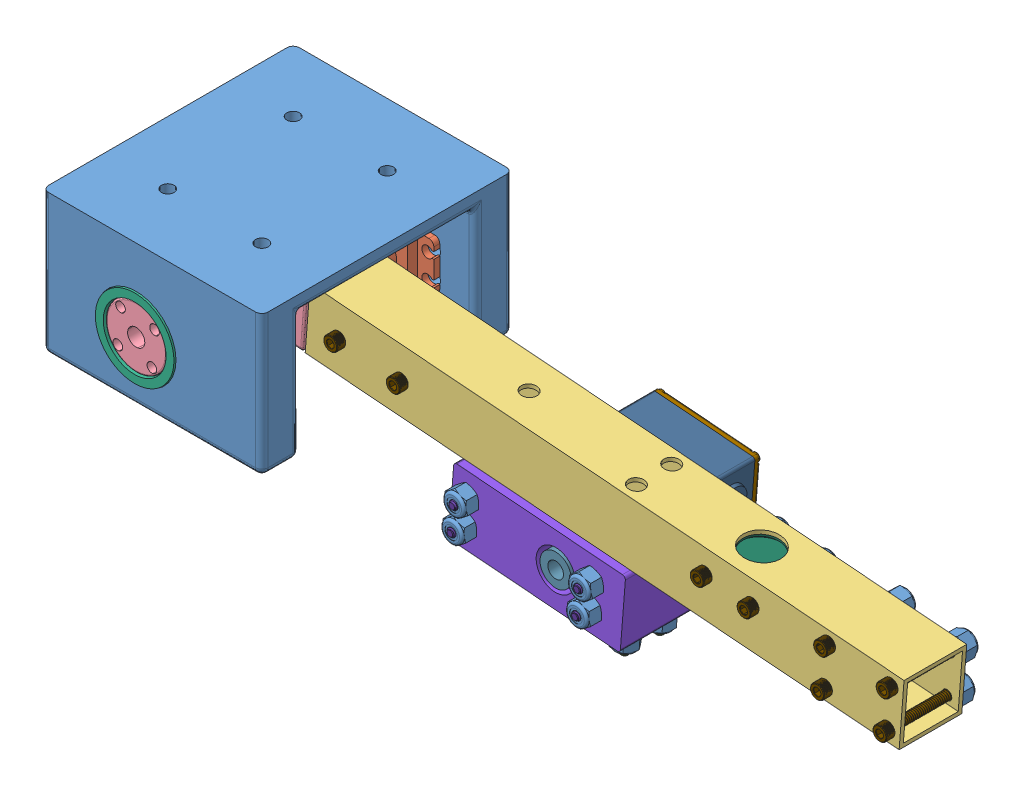
SolidWorks assembly MS-SA-0013d-03-Gripper Arm, configuration Default. Lengths in mm.
Overall size (306.45 94.86 113.6).
51 component instances, 19 part files, 106 mates.
Components (placement in the parent):
- MS-P-0057-03-Gripper Arm Mount-1: MS-P-0057-03-Gripper Arm Mount [Default] at (-52.2477 40.78 53.3156) x (0 0 1) z (0 1 0) size (101.6 88.9 57.15)
- MS-SA-0013b-03-Shoulder Servo Mount Assembly-1: MS-SA-0013b-03-Shoulder Servo Mount Assembly [Default] at (2.0387 62.0863 -50.1865) x (0 1 0) z (1 0 0) size (20 43.5 53.2)
  - MS-C-0032-Gripper Shoulder Servo-1: MS-C-0032-Gripper Shoulder Servo [Default] at (-48.0063 17.0406 -6.2663) x (0 0 -1) z (1 0 0) size (53.2 43.5 20)
- MS-P-0054-03-Box Tubing-1: MS-P-0054-03-Box Tubing [Default] at (11.7266 12.0316 -2.8819) x (0 0 -1) z (0.9969 -0.078677 0) size (25.4 25.4 241.3)
- MS-P-0058-03-Shoulder L Joint-1: MS-P-0058-03-Shoulder L Joint [Default] at (-14.2277 14.08 -2.1834) x (0 0 -1) z (0.9969 -0.078677 0) size (66.61 26.61 88.65)
- 525130.step-1: 525130.step [Default] at (-14.2277 14.08 -19.6459) x (0.078677 0.9969 0) z (0.9969 -0.078677 0) size (25.39 6.35 25.39)
- MS-C-0028-03-Servo Arm Bushing-1: MS-C-0028-03-Servo Arm Bushing [2934T25] at (-14.2277 14.08 34.9006) x (1 0 0) z (0 -1 0) size (38.1 19.05 38.1)
- 97171A170_ HEAT-SET INSERT FOR PLASTIC_V3-1: 97171A170_ HEAT-SET INSERT FOR PLASTIC_V3 [97171A170] at (19.7723 19.08 -40.131) x (-0.536856 0.843674 0) z (-0.843674 -0.536856 0) size (7.14 9.57 7.14)
- 97171A170_ HEAT-SET INSERT FOR PLASTIC_V3-2: 97171A170_ HEAT-SET INSERT FOR PLASTIC_V3 [97171A170] at (19.7723 9.08 -40.131) x (-0.383049 0.923728 0) z (-0.923728 -0.383049 0) size (7.14 9.57 7.14)
- 97171A170_ HEAT-SET INSERT FOR PLASTIC_V3-3: 97171A170_ HEAT-SET INSERT FOR PLASTIC_V3 [97171A170] at (-28.2277 19.08 -40.131) x (-0.940007 -0.341154 0) z (0.341154 -0.940007 0) size (7.14 9.57 7.14)
- 97171A170_ HEAT-SET INSERT FOR PLASTIC_V3-4: 97171A170_ HEAT-SET INSERT FOR PLASTIC_V3 [97171A170] at (-28.2277 9.08 -40.131) x (-0.231744 0.972777 0) z (-0.972777 -0.231744 0) size (7.14 9.57 7.14)
- MS-SA-0013a-03-Hand Servo Mount Assembly-1: MS-SA-0013a-03-Hand Servo Mount Assembly [Default] at (51.6986 -51.9207 16.8315) x (0 0 -1) z (0.9969 -0.078677 0) size (72.39 31.33 69.75)
  - MS-P-0055-03 Hand Servo Mount-1: MS-P-0055-03 Hand Servo Mount [Default] at (12.5808 33.9393 61.1705) size (41.76 27.94 69.75)
  - 11886-1: 11886 [Default] at (71.9223 31.717 49.4945) x (0 1 0) z (0 0 1) size (21 45.43 55.5)
    - 11886_bottom-1: 11886_bottom [Default] at (2.2223 -4.2785 0.9275) size (21 2.43 41.5)
    - 11886_middle-1: 11886_middle [Default] at (2.2223 -1.8785 0.9275) size (21 25.7 42.9)
    - 11886_upper-1: 11886_upper [Default] at (6.1473 23.8215 -5.3225) size (21 8.72 55.5)
    - 11886_top-1: 11886_top [Default] at (2.2223 32.5215 0.7275) size (20 8.6 36.5)
  - MS-C-0027-Servo Horn-1: MS-C-0027-Servo Horn [Default] at (34.0008 33.9393 61.172) x (0 0.962595 -0.270945) z (0 0.270945 0.962595) size (25.39 6.35 25.39)
  - MS-P-0060-03-Hand Servo Pulley-1: MS-P-0060-03-Hand Servo Pulley [Default] at (22.8883 33.9393 61.172) x (0 0.270945 0.962595) z (0 -0.962595 0.270945) size (25.4 23.81 25.4)
- MS-P-0047-Gripper Electromagnet Mount Inside Arm-1: MS-P-0047-Gripper Electromagnet Mount Inside Arm [Default] at (181.8873 -2.9901 -2.8819) x (0.9969 -0.078677 0) z (0 0 1) size (31.75 12.7 22.1)
- 92196A167_18-8 STAINLESS STEEL SOCKET HEAD SCREW-1: 92196A167_18-8 STAINLESS STEEL SOCKET HEAD SCREW [92196A167] at (134.4611 -47.0202 4.2619) x (0.178356 -0.014076 -0.983865) z (-0.078677 -0.9969 0) size (5.73 5.73 42.21)
- 92196A167_18-8 STAINLESS STEEL SOCKET HEAD SCREW-2: 92196A167_18-8 STAINLESS STEEL SOCKET HEAD SCREW [92196A167] at (134.4611 -47.0202 -10.0256) x (-0.009679 0.000764 -0.999953) z (-0.078677 -0.9969 0) size (5.73 5.73 42.21)
- 92196A167_18-8 STAINLESS STEEL SOCKET HEAD SCREW-3: 92196A167_18-8 STAINLESS STEEL SOCKET HEAD SCREW [92196A167] at (83.8186 -43.0235 -2.8819) x (-0.224346 0.017706 -0.974349) z (-0.078677 -0.9969 0) size (5.73 5.73 42.21)
- 92196A169_18-8 STAINLESS STEEL SOCKET HEAD SCREW-7: 92196A169_18-8 STAINLESS STEEL SOCKET HEAD SCREW [92196A169] at (79.7565 -15.0748 19.5306) x (-0.225494 0.974245 0) z (0 0 1) size (5.73 5.73 54.99)
- 92196A169_18-8 STAINLESS STEEL SOCKET HEAD SCREW-8: 92196A169_18-8 STAINLESS STEEL SOCKET HEAD SCREW [92196A169] at (78.9697 -25.0437 19.5306) x (0.191778 -0.981438 0) z (0 0 1) size (5.73 5.73 54.99)
- 92196A169_18-8 STAINLESS STEEL SOCKET HEAD SCREW-9: 92196A169_18-8 STAINLESS STEEL SOCKET HEAD SCREW [92196A169] at (130.2977 -19.0635 19.5306) x (0.056433 -0.998406 0) z (0 0 1) size (5.73 5.73 54.99)
- 92196A169_18-8 STAINLESS STEEL SOCKET HEAD SCREW-10: 92196A169_18-8 STAINLESS STEEL SOCKET HEAD SCREW [92196A169] at (129.511 -29.0325 19.5306) x (-0.049736 -0.998762 0) z (0 0 1) size (5.73 5.73 54.99)
- 92196A166_18-8 STAINLESS STEEL SOCKET HEAD SCREW-13: 92196A166_18-8 STAINLESS STEEL SOCKET HEAD SCREW [92196A166] at (172.7915 2.8236 -21.9319) x (0.59674 0.802434 0) z (0 0 -1) size (5.73 5.73 35.83)
- 92196A166_18-8 STAINLESS STEEL SOCKET HEAD SCREW-15: 92196A166_18-8 STAINLESS STEEL SOCKET HEAD SCREW [92196A166] at (191.7824 1.3248 -21.9319) x (0.615426 0.788195 0) z (0 0 -1) size (5.73 5.73 35.83)
- 90631A009_LOW-STRENGTH STEEL NYLON-INSERT LOCKNUT-1: 90631A009_LOW-STRENGTH STEEL NYLON-INSERT LOCKNUT [90631A009] at (84.493 -34.4775 -2.8819) x (-0.834574 0.065866 -0.546944) z (-0.545249 0.043032 0.837169) size (8.73 6.09 10.08)
- 90631A009_LOW-STRENGTH STEEL NYLON-INSERT LOCKNUT-2: 90631A009_LOW-STRENGTH STEEL NYLON-INSERT LOCKNUT [90631A009] at (135.1356 -38.4743 4.2619) x (-0.922375 0.072795 -0.379375) z (-0.378199 0.029848 0.925243) size (8.73 6.09 10.08)
- 90631A009_LOW-STRENGTH STEEL NYLON-INSERT LOCKNUT-3: 90631A009_LOW-STRENGTH STEEL NYLON-INSERT LOCKNUT [90631A009] at (135.1356 -38.4743 -10.0256) x (-0.982217 0.077518 -0.170998) z (-0.170468 0.013454 0.985271) size (8.73 6.09 10.08)
- 90631A009_LOW-STRENGTH STEEL NYLON-INSERT LOCKNUT-5: 90631A009_LOW-STRENGTH STEEL NYLON-INSERT LOCKNUT [90631A009] at (130.2977 -19.0635 12.9931) x (-0.987107 -0.16006 0) z (-0.16006 0.987107 0) size (8.73 6.09 10.08)
- 90631A009_LOW-STRENGTH STEEL NYLON-INSERT LOCKNUT-7: 90631A009_LOW-STRENGTH STEEL NYLON-INSERT LOCKNUT [90631A009] at (129.511 -29.0325 12.9931) x (-0.994509 -0.104651 0) z (-0.104651 0.994509 0) size (8.73 6.09 10.08)
- 90631A009_LOW-STRENGTH STEEL NYLON-INSERT LOCKNUT-9: 90631A009_LOW-STRENGTH STEEL NYLON-INSERT LOCKNUT [90631A009] at (79.7565 -15.0748 12.9931) x (-0.993677 -0.112278 0) z (-0.112278 0.993677 0) size (8.73 6.09 10.08)
- 90631A009_LOW-STRENGTH STEEL NYLON-INSERT LOCKNUT-11: 90631A009_LOW-STRENGTH STEEL NYLON-INSERT LOCKNUT [90631A009] at (78.9697 -25.0437 12.9931) x (-0.593284 0.804993 0) z (0.804993 0.593284 0) size (8.73 6.09 10.08)
- 90631A009_LOW-STRENGTH STEEL NYLON-INSERT LOCKNUT-13: 90631A009_LOW-STRENGTH STEEL NYLON-INSERT LOCKNUT [90631A009] at (191.7824 1.3248 -15.5819) x (0.013782 -0.999905 0) z (0.999905 0.013782 0) size (8.73 6.09 10.08)
- 90631A009_LOW-STRENGTH STEEL NYLON-INSERT LOCKNUT-15: 90631A009_LOW-STRENGTH STEEL NYLON-INSERT LOCKNUT [90631A009] at (172.7915 2.8236 -15.5819) x (0.187204 -0.982321 0) z (0.982321 0.187204 0) size (8.73 6.09 10.08)
- 92196A166_18-8 STAINLESS STEEL SOCKET HEAD SCREW-17: 92196A166_18-8 STAINLESS STEEL SOCKET HEAD SCREW [92196A166] at (222.7709 3.338 -21.9319) x (-0.902884 0.429884 0) z (0 0 -1) size (5.73 5.73 35.83)
- 92196A166_18-8 STAINLESS STEEL SOCKET HEAD SCREW-18: 92196A166_18-8 STAINLESS STEEL SOCKET HEAD SCREW [92196A166] at (248.0921 1.3396 -21.9319) x (0.224376 0.974503 0) z (0 0 -1) size (5.73 5.73 35.83)
- 92196A166_18-8 STAINLESS STEEL SOCKET HEAD SCREW-19: 92196A166_18-8 STAINLESS STEEL SOCKET HEAD SCREW [92196A166] at (221.5219 -12.4878 -21.9319) x (0.278925 0.960313 0) z (0 0 -1) size (5.73 5.73 35.83)
- 92196A166_18-8 STAINLESS STEEL SOCKET HEAD SCREW-20: 92196A166_18-8 STAINLESS STEEL SOCKET HEAD SCREW [92196A166] at (246.8431 -14.4862 -21.9319) x (0.226233 0.974073 0) z (0 0 -1) size (5.73 5.73 35.83)
- 92196A166_18-8 STAINLESS STEEL SOCKET HEAD SCREW-21: 92196A166_18-8 STAINLESS STEEL SOCKET HEAD SCREW [92196A166] at (24.3873 11.0324 -21.9319) x (0.216747 0.976228 0) z (0 0 -1) size (5.73 5.73 35.83)
- 92196A166_18-8 STAINLESS STEEL SOCKET HEAD SCREW-22: 92196A166_18-8 STAINLESS STEEL SOCKET HEAD SCREW [92196A166] at (49.7085 9.0341 -21.9319) x (0.256336 0.966588 0) z (0 0 -1) size (5.73 5.73 35.83)
- 90631A009_LOW-STRENGTH STEEL NYLON-INSERT LOCKNUT-16: 90631A009_LOW-STRENGTH STEEL NYLON-INSERT LOCKNUT [90631A009] at (222.7709 3.338 -15.5819) x (-0.973129 -0.230259 0) z (0.230259 -0.973129 0) size (8.73 6.09 10.08)
- 90631A009_LOW-STRENGTH STEEL NYLON-INSERT LOCKNUT-17: 90631A009_LOW-STRENGTH STEEL NYLON-INSERT LOCKNUT [90631A009] at (248.0921 1.3396 -15.5819) x (0.296175 -0.955134 0) z (0.955134 0.296175 0) size (8.73 6.09 10.08)
- 90631A009_LOW-STRENGTH STEEL NYLON-INSERT LOCKNUT-18: 90631A009_LOW-STRENGTH STEEL NYLON-INSERT LOCKNUT [90631A009] at (221.5219 -12.4878 -15.5819) x (0.383916 -0.923368 0) z (0.923368 0.383916 0) size (8.73 6.09 10.08)
- 90631A009_LOW-STRENGTH STEEL NYLON-INSERT LOCKNUT-19: 90631A009_LOW-STRENGTH STEEL NYLON-INSERT LOCKNUT [90631A009] at (246.8431 -14.4862 -15.5819) x (0.433613 -0.901099 0) z (0.901099 0.433613 0) size (8.73 6.09 10.08)
- 90631A009_LOW-STRENGTH STEEL NYLON-INSERT LOCKNUT-20: 90631A009_LOW-STRENGTH STEEL NYLON-INSERT LOCKNUT [90631A009] at (49.7085 9.0341 -15.5819) x (0.442359 -0.896838 0) z (0.896838 0.442359 0) size (8.73 6.09 10.08)
- 90631A009_LOW-STRENGTH STEEL NYLON-INSERT LOCKNUT-21: 90631A009_LOW-STRENGTH STEEL NYLON-INSERT LOCKNUT [90631A009] at (24.3873 11.0324 -15.5819) x (-0.623475 -0.781844 0) z (0.781844 -0.623475 0) size (8.73 6.09 10.08)
Mates (geometry in assembly coordinates):
- Distance1: distance = 6.35 mm anti-aligned: plane of MS-P-0047 - Gripper Arm Mount-1 through (95.6161 2.1794 54.1355) normal (0 0 -1); plane of GripperArm-1 through (52.9892 28.9852 43.023) normal (0 0 1)
- Concentric2: concentric aligned: cylinder of GripperArm-1 through (57.5161 21.2294 36.673) axis (0 0 1) radius 3.9688; cylinder of 6389K231_LIGHT DUTY DRY-RUNNING SLEEVE BEARING-1 through (19.4161 14.8794 63.9267) axis (0 0 1) radius 4.7625
- Coincident3: coincident anti-aligned: plane of MS-P-0057-03-Gripper Arm Mount-1 through (36.6523 47.13 53.3156) normal (0 0 1); plane of 6389K231_LIGHT DUTY DRY-RUNNING SLEEVE BEARING-2 through (19.4161 14.8794 69.3755) normal (0 0 -1)
- Concentric4: concentric anti-aligned: cylinder of 6389K231_LIGHT DUTY DRY-RUNNING SLEEVE BEARING-2 through (19.4161 14.8794 63.0255) axis (0 0 1) radius 3.175; cylinder of 90325A181_18-8 STAINLESS STEEL PRECISION SHOULDER SCREW-1 through (14.5574 87.2469 34.4811) axis (0 0 -1) radius 3.175
- Coincident4: coincident anti-aligned: plane of 6389K231_LIGHT DUTY DRY-RUNNING SLEEVE BEARING-2 through (19.4161 14.8794 70.963) normal (0 0 1); plane of 90325A181_18-8 STAINLESS STEEL PRECISION SHOULDER SCREW-1 through (14.5574 82.4844 59.8811) normal (0 0 -1)
- Concentric5: concentric anti-aligned: cylinder of 90325A181_18-8 STAINLESS STEEL PRECISION SHOULDER SCREW-1 through (14.5574 87.2469 34.4811) axis (0 0 -1) radius 1.6764; circle of 90631A011_LOW-STRENGTH STEEL NYLON-INSERT LOCKNUT-1
- Coincident5: coincident anti-aligned: plane of MS-P-0057-03-Gripper Arm Mount-1 through (36.6523 -10.02 38.0756) normal (0 0 -1); plane of 90631A011_LOW-STRENGTH STEEL NYLON-INSERT LOCKNUT-1 through (19.9239 88.4479 56.6755) normal (0 0 1)
- Concentric6: concentric aligned: cylinder of GripperArm-1 through (57.5161 21.2294 36.673) axis (0 0 1) radius 3.9688; cylinder of 98002A930_STEEL BINDING BARRELS AND SCREWS-1 through (19.4161 14.8794 61.9826) axis (0 0 1) radius 3.175
- Coincident6: coincident anti-aligned: plane of GripperArm-1 through (52.9892 28.9852 36.673) normal (0 0 -1); plane of 98002A930_STEEL BINDING BARRELS AND SCREWS-1 through (19.4161 14.8794 70.9629) normal (0 0 1)
- Coincident13: coincident anti-aligned: plane of MS-P-0057-03-Gripper Arm Mount-1 through (36.6523 -10.02 -33.0444) normal (0 0 1); plane of MS-A-0013 - Gripper Arm-1/MS-P-0048 - Servo Mount Piece-3 through (57.5161 40.2794 -42.3845) normal (0 0 -1)
- Concentric12: concentric anti-aligned: cylinder of MS-P-0057-03-Gripper Arm Mount-1 through (3.6323 28.08 53.3166) axis (0 0 -1) radius 2.54; cylinder of MS-A-0013 - Gripper Arm-1/MS-P-0048 - Servo Mount Piece-3 through (76.5661 40.2794 -42.3845) axis (0 0 1) radius 2.54
- Parallel1: parallel anti-aligned: cylinder of MS-P-0057-03-Gripper Arm Mount-1 through (-31.9277 -19.92 53.3166) axis (0 0 -1) radius 2.54; cylinder of MS-A-0013 - Gripper Arm-1/MS-P-0048 - Servo Mount Piece-4 through (38.6261 -10.4206 -42.3845) axis (0 0 1) radius 2.54
- Concentric15: concentric anti-aligned: cylinder of MS-P-0057-03-Gripper Arm Mount-1 through (-31.9277 28.08 53.3166) axis (0 0 -1) radius 2.54; cylinder of MS-A-0013 - Gripper Arm-1/MS-P-0048 - Servo Mount Piece-3 through (38.4661 40.2794 -42.3845) axis (0 0 1) radius 2.54
- Concentric16: concentric anti-aligned: circle of MS-P-0049- Gripper Arm Servo Horn Mount-1; circle of 525130.step-1
- Coincident15: coincident anti-aligned: plane of MS-P-0058-03-Shoulder L Joint-1 through (-14.2277 14.08 -13.2959) normal (0 0 -1); plane of 525130.step-1 through (-14.2277 14.08 -13.2959) normal (0 0 1)
- Concentric18: concentric anti-aligned: circle of MS-A-0013 - Gripper Arm-1/11886-2/11886_top-1; circle of 525130.step-1
- Coincident16: coincident anti-aligned: plane of MS-A-0013 - Gripper Arm-1/11886-2/11886_top-1 through (63.8475 25.5794 10.7295) normal (0 0 1); plane of 525130.step-1 through (-14.2277 14.08 -16.3439) normal (0 0 -1)
- Concentric20: concentric anti-aligned: circle of MS-A-0013 - Gripper Arm-1/MS-P-0048 - Servo Mount Piece-6; circle of MS-P-0047 - Gripper Arm Mount-1
- Coincident17: coincident anti-aligned: plane of MS-P-0057-03-Gripper Arm Mount-1 through (36.6523 -10.02 -33.0444) normal (0 0 1); plane of MS-A-0013 - Gripper Arm-1/MS-P-0048 - Servo Mount Piece-6 through (-14.1477 -19.92 -58.4444) normal (0 0 -1)
- Distance2: distance = 0.635 mm anti-aligned: plane of MS-P-0054-03-Box Tubing-1 through (11.7266 12.0316 -2.8819) normal (-0.9969 0.078677 0); plane of MS-P-0058-03-Shoulder L Joint-1 through (11.0936 12.0816 10.5166) normal (0.9969 -0.078677 0)
- Coincident20: coincident anti-aligned: plane of MS-P-0057-03-Gripper Arm Mount-1 through (36.6523 -10.02 38.0756) normal (0 0 -1); plane of MS-C-0028-03-Servo Arm Bushing-1 through (-14.2277 14.08 38.0756) normal (0 0 1)
- Concentric23: concentric aligned: cylinder of MS-P-0058-03-Shoulder L Joint-1 through (-14.2277 14.08 10.5166) axis (0 0 -1) radius 12.446; cylinder of MS-C-0028-03-Servo Arm Bushing-1 through (-14.2277 14.08 53.9506) axis (0 0 -1) radius 15.9004
- Concentric24: concentric aligned: circle of MS-A-0013 - Gripper Arm-1/MS-C-0029 - D956-WP Servo-1; circle of 525130.step-1
- Coincident21: coincident anti-aligned: plane of MS-A-0013b-03-Shoulder Servo Mount Assembly-1/MS-C-0032-Gripper Shoulder Servo-1 through (-14.2277 14.08 -19.6459) normal (0 0 1); plane of 525130.step-1 through (-14.2277 14.08 -19.6459) normal (0 0 -1)
- Width1: width anti-aligned: plane of MS-P-0058-03-Shoulder L Joint-1 through (60.9168 -2.2969 7.5321) normal (0 0 1); plane of MS-P-0058-03-Shoulder L Joint-1 through (-14.2277 14.08 -13.2959) normal (0 0 -1); plane of MS-P-0054-03-Box Tubing-1 through (253.2779 5.7076 -15.5819) normal (0 0 -1); plane of MS-P-0054-03-Box Tubing-1 through (253.2779 5.7076 9.8181) normal (0 0 1)
- Width2: width aligned: plane of MS-P-0058-03-Shoulder L Joint-1 through (60.9168 -2.2969 -13.2959) normal (-0.078677 -0.9969 0); plane of MS-P-0058-03-Shoulder L Joint-1 through (62.5555 18.4665 -13.2959) normal (0.078677 0.9969 0); plane of MS-P-0054-03-Box Tubing-1 through (251.2795 -19.6136 9.8181) normal (-0.078677 -0.9969 0); plane of MS-P-0054-03-Box Tubing-1 through (253.2779 5.7076 9.8181) normal (0.078677 0.9969 0)
- Concentric25: concentric aligned: circle of MS-P-0057-03-Gripper Arm Mount-1; circle of MS-C-0028-03-Servo Arm Bushing-1
- Coincident23: coincident aligned: plane of MS-P-0057-03-Gripper Arm Mount-1 through (36.6523 47.13 53.3156) normal (0 0 1); plane of MS-P-0058-03-Shoulder L Joint-1 through (-14.2277 14.08 53.3156) normal (0 0 1)
- Parallel2: parallel aligned: plane of MS-P-0057-03-Gripper Arm Mount-1 through (-52.2477 47.13 53.3156) normal (0 1 0); plane of MS-A-0013b-03-Shoulder Servo Mount Assembly-1/MS-C-0032-Gripper Shoulder Servo-1 through (-4.2277 24.08 -30.6459) normal (0 1 0)
- Concentric26: concentric aligned: circle of MS-P-0057-03-Gripper Arm Mount-1; circle of 97171A170_ HEAT-SET INSERT FOR PLASTIC_V3-1
- Coincident24: coincident anti-aligned: plane of MS-P-0057-03-Gripper Arm Mount-1 through (36.6523 47.13 -48.2844) normal (0 0 -1); plane of 97171A170_ HEAT-SET INSERT FOR PLASTIC_V3-1 through (18.4701 21.1265 -48.2844) normal (0 0 1)
- Concentric27: concentric aligned: circle of MS-P-0057-03-Gripper Arm Mount-1; circle of 97171A170_ HEAT-SET INSERT FOR PLASTIC_V3-2
- Coincident25: coincident anti-aligned: plane of MS-P-0057-03-Gripper Arm Mount-1 through (36.6523 47.13 -48.2844) normal (0 0 -1); plane of 97171A170_ HEAT-SET INSERT FOR PLASTIC_V3-2 through (18.8432 11.3207 -48.2844) normal (0 0 1)
- Concentric28: concentric anti-aligned: circle of MS-A-0013b-03-Shoulder Servo Mount Assembly-1/MS-C-0032-Gripper Shoulder Servo-1; circle of 97171A170_ HEAT-SET INSERT FOR PLASTIC_V3-3
- Coincident27: coincident anti-aligned: plane of MS-P-0057-03-Gripper Arm Mount-1 through (36.6523 47.13 -48.2844) normal (0 0 -1); plane of 97171A170_ HEAT-SET INSERT FOR PLASTIC_V3-3 through (-30.5078 18.2524 -48.2844) normal (0 0 1)
- Concentric29: concentric aligned: circle of MS-A-0013b-03-Shoulder Servo Mount Assembly-1/MS-C-0032-Gripper Shoulder Servo-1; circle of 97171A170_ HEAT-SET INSERT FOR PLASTIC_V3-4
- Coincident28: coincident anti-aligned: plane of MS-P-0057-03-Gripper Arm Mount-1 through (36.6523 47.13 -48.2844) normal (0 0 -1); plane of 97171A170_ HEAT-SET INSERT FOR PLASTIC_V3-4 through (-28.7898 11.4396 -48.2844) normal (0 0 1)
- Coincident29: coincident anti-aligned: plane of MS-P-0057-03-Gripper Arm Mount-1 through (36.6523 -10.02 -33.0444) normal (0 0 1); plane of 97171A170_ HEAT-SET INSERT FOR PLASTIC_V3-5 through (25.2931 19.7789 -33.0444) normal (0 0 -1)
- Coincident30: coincident anti-aligned: plane of MS-P-0057-03-Gripper Arm Mount-1 through (36.6523 -10.02 -33.0444) normal (0 0 1); plane of 97171A170_ HEAT-SET INSERT FOR PLASTIC_V3-6 through (25.6708 9.88 -33.0444) normal (0 0 -1)
- Concentric30: concentric aligned: circle of MS-P-0054-03-Box Tubing-1; circle of MS-SA-0013a-03-Hand Servo Mount Assembly-1/MS-P-0055-03 Hand Servo Mount-1
- Concentric31: concentric aligned: circle of MS-P-0054-03-Box Tubing-1; circle of MS-SA-0013a-03-Hand Servo Mount Assembly-1/MS-P-0055-03 Hand Servo Mount-1
- Coincident31: coincident anti-aligned: plane of MS-P-0054-03-Box Tubing-1 through (251.2795 -19.6136 9.8181) normal (-0.078677 -0.9969 0); plane of MS-SA-0013a-03-Hand Servo Mount Assembly-1/MS-P-0055-03 Hand Servo Mount-1 through (116.4488 -8.9727 88.1295) normal (0.078677 0.9969 0)
- Width3: width anti-aligned: plane of MS-P-0054-03-Box Tubing-1 through (253.153 4.125 8.2306) normal (0 0 -1); plane of MS-P-0054-03-Box Tubing-1 through (253.153 4.125 -13.9944) normal (0 0 1); plane of MS-P-0047-Gripper Electromagnet Mount Inside Arm-1 through (167.0607 10.9195 8.1671) normal (0 0 1); plane of MS-P-0047-Gripper Electromagnet Mount Inside Arm-1 through (167.0607 10.9195 -13.9309) normal (0 0 -1)
- Coincident32: coincident anti-aligned: plane of MS-P-0054-03-Box Tubing-1 through (253.153 4.125 8.2306) normal (-0.078677 -0.9969 0); plane of MS-P-0047-Gripper Electromagnet Mount Inside Arm-1 through (182.8864 9.6706 -2.8819) normal (0.078677 0.9969 0)
- Concentric32: concentric aligned: circle of MS-P-0054-03-Box Tubing-1; circle of MS-P-0047-Gripper Electromagnet Mount Inside Arm-1
- LimitAngle1: limit planar angle = 0.078758 rad aligned: plane of MS-P-0054-03-Box Tubing-1 through (253.2779 5.7076 9.8181) normal (0.078677 0.9969 0); plane of MS-P-0057-03-Gripper Arm Mount-1 through (-52.2477 47.13 53.3156) normal (0 1 0)
- Concentric33: concentric aligned: circle of MS-SA-0013a-03-Hand Servo Mount Assembly-1/MS-P-0055-03 Hand Servo Mount-1; circle of 92196A169_18-8 STAINLESS STEEL SOCKET HEAD SCREW-1
- Coincident36: coincident anti-aligned: plane of MS-P-0054-03-Box Tubing-1 through (251.4044 -18.0311 8.2306) normal (0.078677 0.9969 0); plane of 92196A167_18-8 STAINLESS STEEL SOCKET HEAD SCREW-1 through (137.4587 -9.0383 4.2619) normal (-0.078677 -0.9969 0)
- Concentric34: concentric aligned: circle of MS-SA-0013a-03-Hand Servo Mount Assembly-1/MS-P-0055-03 Hand Servo Mount-1; circle of 92196A169_18-8 STAINLESS STEEL SOCKET HEAD SCREW-2
- Coincident37: coincident anti-aligned: plane of MS-P-0054-03-Box Tubing-1 through (251.4044 -18.0311 8.2306) normal (0.078677 0.9969 0); plane of 92196A167_18-8 STAINLESS STEEL SOCKET HEAD SCREW-2 through (137.4587 -9.0383 -10.0256) normal (-0.078677 -0.9969 0)
- Coincident38: coincident anti-aligned: plane of MS-P-0054-03-Box Tubing-1 through (251.4044 -18.0311 8.2306) normal (0.078677 0.9969 0); plane of 92196A167_18-8 STAINLESS STEEL SOCKET HEAD SCREW-3 through (86.8161 -5.0416 -2.8819) normal (-0.078677 -0.9969 0)
- Concentric35: concentric aligned: circle of MS-SA-0013a-03-Hand Servo Mount Assembly-1/MS-P-0055-03 Hand Servo Mount-1; circle of 92196A169_18-8 STAINLESS STEEL SOCKET HEAD SCREW-3
- Concentric37: concentric aligned: circle of MS-SA-0013a-03-Hand Servo Mount Assembly-1/MS-P-0055-03 Hand Servo Mount-1; circle of 92196A169_18-8 STAINLESS STEEL SOCKET HEAD SCREW-7
- Concentric38: concentric aligned: circle of MS-SA-0013a-03-Hand Servo Mount Assembly-1/MS-P-0055-03 Hand Servo Mount-1; circle of 92196A169_18-8 STAINLESS STEEL SOCKET HEAD SCREW-8
- Concentric39: concentric aligned: circle of MS-SA-0013a-03-Hand Servo Mount Assembly-1/MS-P-0055-03 Hand Servo Mount-1; circle of 92196A169_18-8 STAINLESS STEEL SOCKET HEAD SCREW-9
- Concentric40: concentric aligned: circle of MS-SA-0013a-03-Hand Servo Mount Assembly-1/MS-P-0055-03 Hand Servo Mount-1; circle of 92196A169_18-8 STAINLESS STEEL SOCKET HEAD SCREW-10
- Concentric41: concentric aligned: circle of MS-P-0047-Gripper Electromagnet Mount Inside Arm-1; circle of 92196A169_18-8 STAINLESS STEEL SOCKET HEAD SCREW-13
- Concentric42: concentric aligned: circle of MS-P-0047-Gripper Electromagnet Mount Inside Arm-1; circle of 92196A169_18-8 STAINLESS STEEL SOCKET HEAD SCREW-15
- Concentric43: concentric anti-aligned: circle of 90631A009_LOW-STRENGTH STEEL NYLON-INSERT LOCKNUT-1; circle of MS-SA-0013a-03-Hand Servo Mount Assembly-1/MS-P-0055-03 Hand Servo Mount-1
- Coincident52: coincident anti-aligned: plane of MS-SA-0013a-03-Hand Servo Mount Assembly-1/MS-P-0055-03 Hand Servo Mount-1 through (114.2506 -36.826 88.1295) normal (-0.078677 -0.9969 0); plane of 90631A009_LOW-STRENGTH STEEL NYLON-INSERT LOCKNUT-1 through (92.2594 -35.0905 -6.8244) normal (0.078677 0.9969 0)
- Concentric44: concentric anti-aligned: circle of MS-SA-0013a-03-Hand Servo Mount Assembly-1/MS-P-0055-03 Hand Servo Mount-1; circle of 90631A009_LOW-STRENGTH STEEL NYLON-INSERT LOCKNUT-2
- Coincident53: coincident anti-aligned: plane of MS-SA-0013a-03-Hand Servo Mount Assembly-1/MS-P-0055-03 Hand Servo Mount-1 through (114.2506 -36.826 88.1295) normal (-0.078677 -0.9969 0); plane of 90631A009_LOW-STRENGTH STEEL NYLON-INSERT LOCKNUT-2 through (142.022 -39.0178 -1.0781) normal (0.078677 0.9969 0)
- Coincident54: coincident anti-aligned: plane of MS-SA-0013a-03-Hand Servo Mount Assembly-1/MS-P-0055-03 Hand Servo Mount-1 through (114.2506 -36.826 88.1295) normal (-0.078677 -0.9969 0); plane of 90631A009_LOW-STRENGTH STEEL NYLON-INSERT LOCKNUT-3 through (140.7125 -38.9145 -16.7292) normal (0.078677 0.9969 0)
- Concentric45: concentric anti-aligned: circle of MS-SA-0013a-03-Hand Servo Mount Assembly-1/MS-P-0055-03 Hand Servo Mount-1; circle of 90631A009_LOW-STRENGTH STEEL NYLON-INSERT LOCKNUT-3
- Coincident57: coincident anti-aligned: plane of MS-SA-0013a-03-Hand Servo Mount Assembly-1/11886-1/11886_upper-1 through (83.1227 -30.8886 -31.2694) normal (0 0 -1); plane of 92196A169_18-8 STAINLESS STEEL SOCKET HEAD SCREW-7 through (79.7565 -15.0748 -31.2694) normal (0 0 1)
- Coincident58: coincident anti-aligned: plane of MS-SA-0013a-03-Hand Servo Mount Assembly-1/11886-1/11886_upper-1 through (83.1227 -30.8886 -31.2694) normal (0 0 -1); plane of 92196A169_18-8 STAINLESS STEEL SOCKET HEAD SCREW-8 through (78.9697 -25.0437 -31.2694) normal (0 0 1)
- Coincident59: coincident anti-aligned: plane of MS-SA-0013a-03-Hand Servo Mount Assembly-1/11886-1/11886_upper-1 through (83.1227 -30.8886 -31.2694) normal (0 0 -1); plane of 92196A169_18-8 STAINLESS STEEL SOCKET HEAD SCREW-9 through (130.2977 -19.0635 -31.2694) normal (0 0 1)
- Coincident60: coincident anti-aligned: plane of MS-SA-0013a-03-Hand Servo Mount Assembly-1/11886-1/11886_upper-1 through (83.1227 -30.8886 -31.2694) normal (0 0 -1); plane of 92196A169_18-8 STAINLESS STEEL SOCKET HEAD SCREW-10 through (129.511 -29.0325 -31.2694) normal (0 0 1)
- Concentric47: concentric anti-aligned: circle of MS-SA-0013a-03-Hand Servo Mount Assembly-1/MS-P-0055-03 Hand Servo Mount-1; circle of 90631A009_LOW-STRENGTH STEEL NYLON-INSERT LOCKNUT-5
- Coincident61: coincident anti-aligned: plane of MS-SA-0013a-03-Hand Servo Mount Assembly-1/MS-P-0055-03 Hand Servo Mount-1 through (115.3512 -22.8995 12.9931) normal (0 0 1); plane of 90631A009_LOW-STRENGTH STEEL NYLON-INSERT LOCKNUT-5 through (135.8174 -25.8288 12.9931) normal (0 0 -1)
- Concentric50: concentric anti-aligned: circle of MS-SA-0013a-03-Hand Servo Mount Assembly-1/MS-P-0055-03 Hand Servo Mount-1; circle of 90631A009_LOW-STRENGTH STEEL NYLON-INSERT LOCKNUT-7
- Coincident63: coincident anti-aligned: plane of MS-SA-0013a-03-Hand Servo Mount Assembly-1/MS-P-0055-03 Hand Servo Mount-1 through (115.3512 -22.8995 12.9931) normal (0 0 1); plane of 90631A009_LOW-STRENGTH STEEL NYLON-INSERT LOCKNUT-7 through (134.6439 -36.0956 12.9931) normal (0 0 -1)
- Concentric51: concentric anti-aligned: circle of MS-SA-0013a-03-Hand Servo Mount Assembly-1/MS-P-0055-03 Hand Servo Mount-1; circle of 90631A009_LOW-STRENGTH STEEL NYLON-INSERT LOCKNUT-9
- Coincident64: coincident anti-aligned: plane of MS-SA-0013a-03-Hand Servo Mount Assembly-1/MS-P-0055-03 Hand Servo Mount-1 through (115.3512 -22.8995 12.9931) normal (0 0 1); plane of 90631A009_LOW-STRENGTH STEEL NYLON-INSERT LOCKNUT-9 through (84.9435 -22.0983 12.9931) normal (0 0 -1)
- Concentric52: concentric anti-aligned: circle of MS-SA-0013a-03-Hand Servo Mount Assembly-1/MS-P-0055-03 Hand Servo Mount-1; circle of 90631A009_LOW-STRENGTH STEEL NYLON-INSERT LOCKNUT-11
- Coincident65: coincident anti-aligned: plane of MS-SA-0013a-03-Hand Servo Mount Assembly-1/MS-P-0055-03 Hand Servo Mount-1 through (115.3512 -22.8995 12.9931) normal (0 0 1); plane of 90631A009_LOW-STRENGTH STEEL NYLON-INSERT LOCKNUT-11 through (75.4728 -33.0441 12.9931) normal (0 0 -1)
- Concentric53: concentric anti-aligned: circle of MS-P-0054-03-Box Tubing-1; circle of 90631A009_LOW-STRENGTH STEEL NYLON-INSERT LOCKNUT-13
- Coincident66: coincident anti-aligned: plane of MS-P-0054-03-Box Tubing-1 through (253.2779 5.7076 -15.5819) normal (0 0 -1); plane of 90631A009_LOW-STRENGTH STEEL NYLON-INSERT LOCKNUT-13 through (184.1615 5.5858 -15.5819) normal (0 0 1)
- Concentric54: concentric anti-aligned: circle of MS-P-0054-03-Box Tubing-1; circle of 90631A009_LOW-STRENGTH STEEL NYLON-INSERT LOCKNUT-15
- Coincident67: coincident anti-aligned: plane of MS-P-0054-03-Box Tubing-1 through (253.2779 5.7076 -15.5819) normal (0 0 -1); plane of 90631A009_LOW-STRENGTH STEEL NYLON-INSERT LOCKNUT-15 through (164.5464 5.6965 -15.5819) normal (0 0 1)
- Coincident68: coincident anti-aligned: plane of MS-P-0054-03-Box Tubing-1 through (253.2779 5.7076 9.8181) normal (0 0 1); plane of 92196A166_18-8 STAINLESS STEEL SOCKET HEAD SCREW-13 through (172.7915 2.8236 9.8181) normal (0 0 -1)
- Coincident69: coincident anti-aligned: plane of MS-P-0054-03-Box Tubing-1 through (253.2779 5.7076 9.8181) normal (0 0 1); plane of 92196A166_18-8 STAINLESS STEEL SOCKET HEAD SCREW-15 through (191.7824 1.3248 9.8181) normal (0 0 -1)
- Concentric55: concentric anti-aligned: circle of MS-P-0054-03-Box Tubing-1; circle of 92196A166_18-8 STAINLESS STEEL SOCKET HEAD SCREW-17
- Coincident70: coincident anti-aligned: plane of MS-P-0054-03-Box Tubing-1 through (253.2779 5.7076 9.8181) normal (0 0 1); plane of 92196A166_18-8 STAINLESS STEEL SOCKET HEAD SCREW-17 through (222.7709 3.338 9.8181) normal (0 0 -1)
- Coincident71: coincident: plane of MS-P-0054-03-Box Tubing-1 through (241.8883 -63.5982 9.8181) normal (0 0 1); plane of 92196A166_18-8 STAINLESS STEEL SOCKET HEAD SCREW-18
- Concentric56: concentric anti-aligned: circle of MS-P-0054-03-Box Tubing-1; circle of 92196A166_18-8 STAINLESS STEEL SOCKET HEAD SCREW-18
- Coincident72: coincident: plane of MS-P-0054-03-Box Tubing-1 through (241.8883 -63.5982 9.8181) normal (0 0 1); plane of 92196A166_18-8 STAINLESS STEEL SOCKET HEAD SCREW-19
- Concentric57: concentric anti-aligned: circle of MS-P-0054-03-Box Tubing-1; circle of 92196A166_18-8 STAINLESS STEEL SOCKET HEAD SCREW-19
- Coincident73: coincident anti-aligned: plane of MS-P-0054-03-Box Tubing-1 through (253.2779 5.7076 9.8181) normal (0 0 1); plane of 92196A166_18-8 STAINLESS STEEL SOCKET HEAD SCREW-20 through (246.8431 -14.4862 9.8181) normal (0 0 -1)
- Concentric58: concentric anti-aligned: circle of MS-P-0054-03-Box Tubing-1; circle of 92196A166_18-8 STAINLESS STEEL SOCKET HEAD SCREW-20
- Coincident74: coincident anti-aligned: plane of MS-P-0054-03-Box Tubing-1 through (253.2779 5.7076 9.8181) normal (0 0 1); plane of 92196A166_18-8 STAINLESS STEEL SOCKET HEAD SCREW-21 through (24.3873 11.0324 9.8181) normal (0 0 -1)
- Concentric59: concentric aligned: circle of MS-P-0054-03-Box Tubing-1; circle of 92196A166_18-8 STAINLESS STEEL SOCKET HEAD SCREW-21
- Coincident75: coincident anti-aligned: plane of MS-P-0054-03-Box Tubing-1 through (253.2779 5.7076 9.8181) normal (0 0 1); plane of 92196A166_18-8 STAINLESS STEEL SOCKET HEAD SCREW-22 through (49.7085 9.0341 9.8181) normal (0 0 -1)
- Concentric60: concentric aligned: circle of MS-P-0054-03-Box Tubing-1; circle of 92196A166_18-8 STAINLESS STEEL SOCKET HEAD SCREW-22
- Concentric61: concentric aligned: circle of MS-P-0054-03-Box Tubing-1; circle of 90631A009_LOW-STRENGTH STEEL NYLON-INSERT LOCKNUT-16
- Coincident77: coincident anti-aligned: plane of MS-P-0054-03-Box Tubing-1 through (253.2779 5.7076 -15.5819) normal (0 0 -1); plane of 90631A009_LOW-STRENGTH STEEL NYLON-INSERT LOCKNUT-16 through (225.2781 11.7015 -15.5819) normal (0 0 1)
- Coincident78: coincident anti-aligned: plane of MS-P-0054-03-Box Tubing-1 through (253.2779 5.7076 -15.5819) normal (0 0 -1); plane of 90631A009_LOW-STRENGTH STEEL NYLON-INSERT LOCKNUT-17 through (239.5769 3.2698 -15.5819) normal (0 0 1)
- Concentric62: concentric aligned: circle of MS-P-0054-03-Box Tubing-1; circle of 90631A009_LOW-STRENGTH STEEL NYLON-INSERT LOCKNUT-17
- Coincident79: coincident anti-aligned: plane of MS-P-0054-03-Box Tubing-1 through (253.2779 5.7076 -15.5819) normal (0 0 -1); plane of 90631A009_LOW-STRENGTH STEEL NYLON-INSERT LOCKNUT-18 through (212.8638 -11.3597 -15.5819) normal (0 0 1)
- Concentric63: concentric aligned: circle of MS-P-0054-03-Box Tubing-1; circle of 90631A009_LOW-STRENGTH STEEL NYLON-INSERT LOCKNUT-18
- Coincident80: coincident anti-aligned: plane of MS-P-0054-03-Box Tubing-1 through (253.2779 5.7076 -15.5819) normal (0 0 -1); plane of 90631A009_LOW-STRENGTH STEEL NYLON-INSERT LOCKNUT-19 through (238.1365 -13.8311 -15.5819) normal (0 0 1)
- Concentric64: concentric aligned: circle of MS-P-0054-03-Box Tubing-1; circle of 90631A009_LOW-STRENGTH STEEL NYLON-INSERT LOCKNUT-19
- Coincident81: coincident anti-aligned: plane of MS-P-0054-03-Box Tubing-1 through (253.2779 5.7076 -15.5819) normal (0 0 -1); plane of 90631A009_LOW-STRENGTH STEEL NYLON-INSERT LOCKNUT-20 through (40.9959 9.6044 -15.5819) normal (0 0 1)
- Concentric65: concentric aligned: circle of MS-P-0054-03-Box Tubing-1; circle of 90631A009_LOW-STRENGTH STEEL NYLON-INSERT LOCKNUT-20
- Coincident82: coincident anti-aligned: plane of MS-P-0054-03-Box Tubing-1 through (253.2779 5.7076 -15.5819) normal (0 0 -1); plane of 90631A009_LOW-STRENGTH STEEL NYLON-INSERT LOCKNUT-21 through (21.1972 19.1601 -15.5819) normal (0 0 1)
- Concentric66: concentric anti-aligned: circle of MS-P-0054-03-Box Tubing-1; circle of 90631A009_LOW-STRENGTH STEEL NYLON-INSERT LOCKNUT-21
